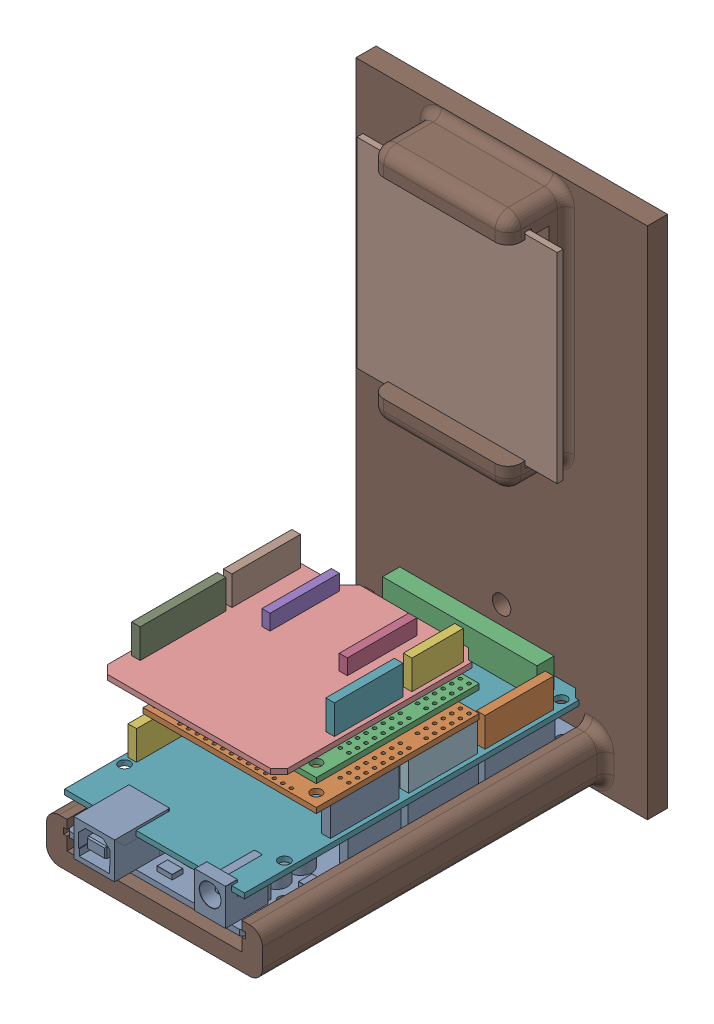
SolidWorks assembly Right_Saddle_Bag, configuration Default. Lengths in mm.
Overall size (86.36 152.4 113.94).
7 component instances, 6 part files, 19 mates.
Components (placement in the parent):
- ArduinoMega-1: ArduinoMega [Default] at (-37.9368 29.0746 -15.9196) x (0 0 1) z (0 -1 0) size (107.95 53.42 12.95)
- dual-tb9051ftg-motor-driver-shield-2: dual-tb9051ftg-motor-driver-shield [Default] at (-12.3209 47.7944 12.5284) x (0 0 -1) z (0 1 0) size (48.26 51.31 7.68)
- dual-tb9051ftg-motor-driver-shield-3: dual-tb9051ftg-motor-driver-shield [Default] at (-12.3209 55.4692 12.5284) x (0 0 -1) z (0 1 0) size (48.26 51.31 7.68)
- xbee shield-1: xbee shield [Default] at (-11.3049 63.906 24.5934) x (0 0 -1) z (1 0 0) size (60.32 10.16 53.34)
- Right_Saddle_Bag_Rev2-1: Right_Saddle_Bag_Rev2 [Default] at (-82.3868 15.9936 -72.714) x (1 0 0) z (0 -1 0) size (86.36 107.59 152.4)
- Arduino Mega Protoboard-1: Arduino Mega Protoboard [Default] at (-11.2287 38.3964 34.8804) x (0 0 -1) z (1 0 0) size (101.6 10.16 53.34)
- SensorBoard-1: SensorBoard [Default] at (-37.9368 130.4841 -56.5596) x (1 0 0) z (0 -1 0) size (59.31 1.78 59.31)
Mates (geometry in assembly coordinates):
- Coincident16: coincident aligned: plane of ArduinoMega-1 through (-15.0387 37.6344 -35.7316) normal (0 0 -1); plane of dual-tb9051ftg-motor-driver-shield-2 through (-12.3209 49.3692 -35.7316) normal (0 0 -1)
- Width1: width anti-aligned: plane of dual-tb9051ftg-motor-driver-shield-2 through (-12.3209 49.3692 12.5284) normal (1 0 0); plane of dual-tb9051ftg-motor-driver-shield-2 through (-63.6289 49.3692 -35.7316) normal (-1 0 0); plane of ArduinoMega-1 through (-63.3749 37.6344 -52.5972) normal (-1 0 0); plane of ArduinoMega-1 through (-12.5749 37.6344 -35.7316) normal (1 0 0)
- Concentric4: concentric aligned: cylinder of dual-tb9051ftg-motor-driver-shield-2 through (-16.1309 49.3692 8.7184) axis (0 -1 0) radius 1.5875; cylinder of dual-tb9051ftg-motor-driver-shield-3 through (-16.1309 57.044 8.7184) axis (0 -1 0) radius 1.5875
- Concentric5: concentric aligned: cylinder of dual-tb9051ftg-motor-driver-shield-2 through (-50.4749 49.3692 -31.1596) axis (0 -1 0) radius 1.0922; cylinder of dual-tb9051ftg-motor-driver-shield-3 through (-50.4749 57.044 -31.1596) axis (0 -1 0) radius 1.0922
- Coincident19: coincident anti-aligned: plane of dual-tb9051ftg-motor-driver-shield-2 through (-12.3209 55.4692 12.5284) normal (0 1 0); plane of dual-tb9051ftg-motor-driver-shield-3 through (-12.3209 55.4692 12.5284) normal (0 -1 0)
- Parallel8: parallel aligned: plane of dual-tb9051ftg-motor-driver-shield-3 through (-12.3209 57.044 -35.7316) normal (0 0 -1); plane of xbee shield-1 through (-47.7379 64.668 -35.7316) normal (0 0 -1)
- Coincident21: coincident anti-aligned: plane of dual-tb9051ftg-motor-driver-shield-3 through (-12.3209 63.144 12.5284) normal (0 1 0); plane of xbee shield-1 through (-11.3049 63.144 24.5934) normal (0 -1 0)
- Width2: width anti-aligned: plane of xbee shield-1 through (-11.3049 64.668 22.0534) normal (1 0 0); plane of xbee shield-1 through (-64.6449 64.668 22.0534) normal (-1 0 0); plane of dual-tb9051ftg-motor-driver-shield-3 through (-63.6289 57.044 -35.7316) normal (-1 0 0); plane of dual-tb9051ftg-motor-driver-shield-3 through (-12.3209 57.044 12.5284) normal (1 0 0)
- Coincident22: coincident aligned: plane of dual-tb9051ftg-motor-driver-shield-3 through (-12.3209 57.044 -35.7316) normal (0 0 -1); plane of xbee shield-1 through (-47.7379 64.668 -35.7316) normal (0 0 -1)
- Coincident23: coincident aligned: plane of ArduinoMega-1 through (-64.6449 27.4236 -66.7196) normal (0 0 -1); plane of Arduino Mega Protoboard-1 through (-48.2967 39.1584 -66.7196) normal (0 0 -1)
- Coincident24: coincident anti-aligned: plane of ArduinoMega-1 through (-12.5749 37.6344 -14.9036) normal (0 1 0); plane of Arduino Mega Protoboard-1 through (-11.2287 37.6344 34.8804) normal (0 -1 0)
- Coincident25: coincident aligned: plane of ArduinoMega-1 through (-11.2287 27.4236 -66.7196) normal (1 0 0); plane of Arduino Mega Protoboard-1 through (-11.2287 39.1584 34.8804) normal (1 0 0)
- Coincident26: coincident anti-aligned: plane of dual-tb9051ftg-motor-driver-shield-2 through (-12.3209 47.7944 12.5284) normal (0 -1 0); plane of Arduino Mega Protoboard-1 through (-11.2287 47.7944 34.8804) normal (0 1 0)
- Coincident27: coincident anti-aligned: plane of ArduinoMega-1 through (-64.6449 27.4236 -66.7196) normal (0 0 -1); plane of Right_Saddle_Bag_Rev2-1 through (-82.3868 15.9936 -66.7196) normal (0 0 1)
- Coincident28: coincident anti-aligned: plane of ArduinoMega-1 through (-11.2287 27.4236 34.8804) normal (0 -1 0); plane of Right_Saddle_Bag_Rev2-1 through (-82.3868 27.4236 34.8804) normal (0 1 0)
- Width3: width aligned: plane of ArduinoMega-1 through (-11.2287 27.4236 -66.7196) normal (1 0 0); plane of Right_Saddle_Bag_Rev2-1 through (-64.6449 27.4236 -66.7196) normal (-1 0 0); plane of ArduinoMega-1 through (-63.8448 15.9936 34.8804) normal (1 0 0); plane of Right_Saddle_Bag_Rev2-1 through (-12.0288 15.9936 34.8804) normal (-1 0 0)
- Coincident29: coincident anti-aligned: plane of Right_Saddle_Bag_Rev2-1 through (-58.2568 15.9936 -56.5596) normal (0 0 1); plane of SensorBoard-1 through (-37.9368 130.4841 -56.5596) normal (0 0 -1)
- Width4: width anti-aligned: plane of SensorBoard-1 through (-8.2823 100.8296 -54.7816) normal (1 0 0); plane of Right_Saddle_Bag_Rev2-1 through (-67.5913 100.8296 -54.7816) normal (-1 0 0); plane of SensorBoard-1 through (-58.2568 15.9936 -72.714) normal (-1 0 0); plane of Right_Saddle_Bag_Rev2-1 through (-17.6168 15.9936 -72.714) normal (1 0 0)
- Width5: width anti-aligned: plane of SensorBoard-1 through (-67.5913 160.1386 -54.7816) normal (0 1 0); plane of Right_Saddle_Bag_Rev2-1 through (-67.5913 100.8296 -54.7816) normal (0 -1 0); plane of SensorBoard-1 through (-58.2568 160.7736 -72.714) normal (0 -1 0); plane of Right_Saddle_Bag_Rev2-1 through (-58.2568 100.1946 -72.714) normal (0 1 0)
